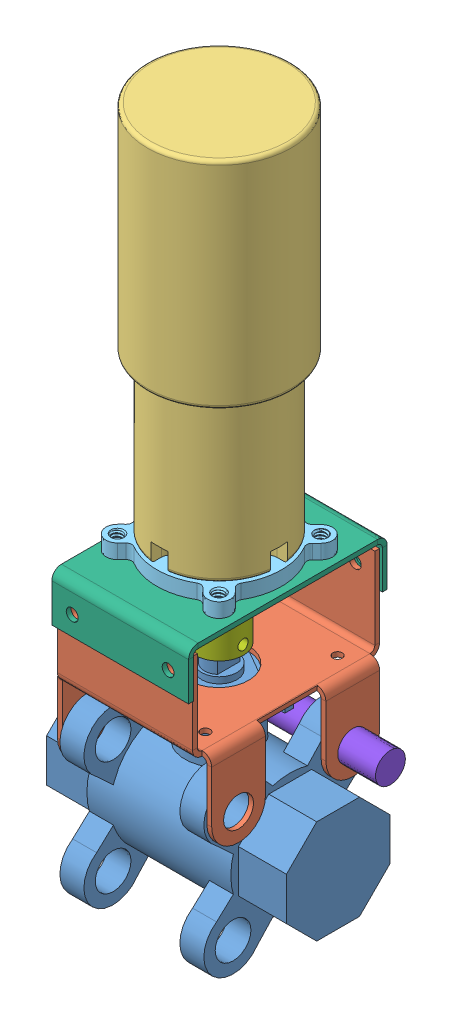
SolidWorks assembly Test-Bracket-Fit, configuration Default. Lengths in mm.
Overall size (63.5 182.63 52.58).
8 component instances, 8 part files, 17 mates.
Components (placement in the parent):
- Sharpe 39036-1: Sharpe 39036 [Default] at (-57.1499 -3.3368 16.1541) size (63.5 64.02 45.72)
- Base-sheetmetal-2: Base-sheetmetal [Default] at (-38.0085 26.79 16.1541) x (1 0 0) z (0 0 -1) size (40.82 46.26 49.53)
- Motor_12VDC_638263-1: Motor_12VDC_638263 [Default] at (-38.0997 54.535 15.8703) x (-0.002411 0 0.999997) z (0.999997 0 0.002411) size (38 101.9 38)
- Motor_12VDC_638263_shaft-1: Motor_12VDC_638263_shaft [Default] at (-38.0999 54.535 15.8701) x (-0.162768 0 0.986664) z (0.986664 0 0.162768) size (6 16.2 6)
- 555174-1: 555174 [Default] at (-38.0999 57.535 15.8701) x (0.002411 0 -0.999997) z (-0.999997 0 -0.002411) size (33.02 4.05 33.02)
- Top-sheetmetal-1: Top-sheetmetal [Default] at (-38.0085 52.19 15.9001) x (-1 0 0) z (0 0 1) size (36.2 12.7 52.58)
- shaft-adapter-forgear-1: shaft-adapter-forgear [Default] at (-38.0999 47.827 15.8701) size (25.32 21.35 25.32)
- Sharpe 39036 Bolt-1: Sharpe 39036 Bolt [Default] at (-63.4999 11.7762 1.0411) size (55.88 14.66 12.7)
Mates (geometry in assembly coordinates):
- Concentric3: concentric: cylinder of Sharpe 39036-1 through (-19.0499 11.7762 31.2671) axis (-1 0 0) radius 4.7307; circle of Base-sheetmetal-2
- Coincident5: coincident: plane of Sharpe 39036-1 through (-57.1499 -3.3368 16.1541) normal (-1 0 0); plane of Base-sheetmetal-2 through (-57.1499 46.3837 16.1541) normal (1 0 0)
- Concentric4: concentric: circle of Sharpe 39036-1; circle of Base-sheetmetal-2
- Coincident6: coincident: plane of Motor_12VDC_638263-1 through (-38.0997 54.535 15.8703) normal (0 -1 0); plane of Motor_12VDC_638263_shaft-1 through (-38.0999 54.535 15.8701) normal (0 1 0)
- Concentric5: concentric: circle of Motor_12VDC_638263-1; circle of Motor_12VDC_638263_shaft-1
- Distance1: distance = 0.508 mm: plane of Motor_12VDC_638263_shaft-1 through (-38.0999 38.335 15.8701) normal (0 -1 0); plane of Sharpe 39036-1 through (-38.0999 37.827 15.8701) normal (0 1 0)
- Concentric6: concentric: cylinder of Sharpe 39036-1 through (-38.0999 23.222 15.8701) axis (0 -1 0) radius 9.0805; cylinder of Motor_12VDC_638263_shaft-1 through (-38.0999 38.335 15.8701) axis (0 1 0) radius 3
- Coincident12: coincident: plane of Motor_12VDC_638263-1 through (-38.0997 57.535 15.8703) normal (0 -1 0); plane of 555174-1 through (-38.0999 57.535 15.8701) normal (0 1 0)
- Concentric7: concentric: cylinder of Motor_12VDC_638263-1 through (-38.0997 99.335 15.8703) axis (0 -1 0) radius 16; cylinder of 555174-1 through (-38.0999 57.535 15.8701) axis (0 1 0) radius 10.033
- Coincident13: coincident: circle of Motor_12VDC_638263-1; cylinder of 555174-1 through (-47.2698 56.265 6.6557) axis (0 -1 0) radius 1.5
- Coincident14: coincident: plane of Base-sheetmetal-2 through (-38.0085 26.79 40.9191) normal (0 0 1); plane of Top-sheetmetal-1 through (-38.0085 52.19 40.9191) normal (0 0 -1)
- Concentric8: concentric: cylinder of Base-sheetmetal-2 through (-25.3085 45.84 40.9191) axis (0 0 -1) radius 1.5875; cylinder of Top-sheetmetal-1 through (-25.3085 45.84 42.1891) axis (0 0 -1) radius 1.5875
- Concentric9: concentric: cylinder of Base-sheetmetal-2 through (-50.7085 45.84 40.9191) axis (0 0 -1) radius 1.5875; cylinder of Top-sheetmetal-1 through (-50.7085 45.84 42.1891) axis (0 0 -1) radius 1.5875
- Coincident16: coincident: plane of Sharpe 39036-1 through (-38.0999 37.827 15.8701) normal (0 1 0); plane of shaft-adapter-forgear-1 through (-38.0999 37.827 15.8701) normal (0 -1 0)
- Concentric14: concentric: cylinder of Motor_12VDC_638263_shaft-1 through (-38.0999 38.335 15.8701) axis (0 1 0) radius 3; cylinder of shaft-adapter-forgear-1 through (-38.0999 37.827 15.8701) axis (0 1 0) radius 3.1
- Coincident17: coincident: plane of Base-sheetmetal-2 through (-58.4199 46.3837 16.1541) normal (-1 0 0); plane of Sharpe 39036 Bolt-1 through (-58.4199 11.7762 1.0411) normal (1 0 0)
- Concentric15: concentric: cylinder of Sharpe 39036-1 through (-50.7999 11.7762 1.0411) axis (-1 0 0) radius 4.7307; cylinder of Sharpe 39036 Bolt-1 through (-7.6199 11.7762 1.0411) axis (-1 0 0) radius 3.9688
